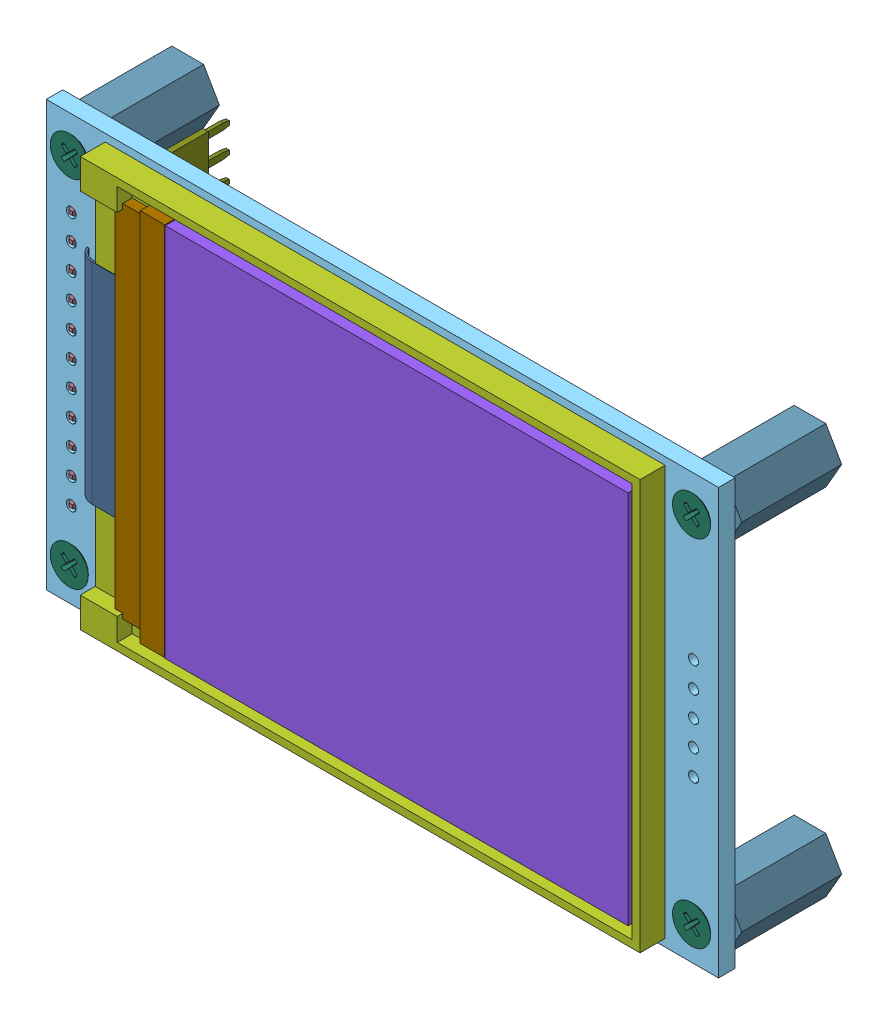
SolidWorks assembly 2.2 TFT LCD Display Modul 240x320, configuration Default. Lengths in mm.
Overall size (68.6 42.5 25.74).
27 component instances, 17 part files, 24 mates.
Components (placement in the parent):
- COMPOUND007-1: COMPOUND007 [Default] at origin size (0.9 1.7 0.55)
- SOLID001-1: SOLID001 [Default] at origin size (0.9 1.7 0.9)
- SD_Card_Slot-1: SD_Card_Slot [Default] at origin (suppressed, hidden)
- PZ_TransistorSMD-1: PZ_TransistorSMD [Default] at origin size (3 2.5 1.11)
- COMPOUND005-1: COMPOUND005 [Default] at origin size (0.9 1.7 0.55)
- Pad010-1: Pad010 [Default] at origin size (67.25 42.5 6.91)
- PZ_TransistorSMD001-1: PZ_TransistorSMD001 [Default] at origin size (2.5 3 1.11)
- Extrude002-1: Extrude002 [Default] at (0.1292 9.9042 1.65) size (56 41 2.5)
- Display001-1: Display001 [Default] at (0.0633 0.4424 2.65) size (46.3 37.5 1.5)
- DisplayConnecter001-1: DisplayConnecter001 [Default] at origin size (5.48 37.5 2.5)
- Body003-1: Body003 [Default] at origin size (5.2 21 3.4)
- COMPOUND004-1: COMPOUND004 [Default] at origin size (0.9 1.7 0.55)
- COMPOUND006-1: COMPOUND006 [Default] at origin size (0.9 1.7 0.55)
- HEADER 11-2: HEADER 11 [Default] at (-31.125 12.7 0.1949) x (0 -1 0) z (1 0 0) size (27.94 12.86 2.54)
- hex spacer standoff nut_M3 L10-1: hex spacer standoff nut_M3 L10 [Default] at (-31.125 -17.75 -10) size (6.35 5.5 10)
- hex spacer standoff nut_M3 L10-2: hex spacer standoff nut_M3 L10 [Default] at (-31.125 17.75 -10) size (6.35 5.5 10)
- hex spacer standoff nut_M3 L10-8: hex spacer standoff nut_M3 L10 [Default] at (31.125 -17.75 -10) size (6.35 5.5 10)
- hex spacer standoff nut_M3 L10-9: hex spacer standoff nut_M3 L10 [Default] at (31.125 17.75 -10) size (6.35 5.5 10)
- M3_3MM-1: M3_3MM [Default] at (-31.125 17.75 1.85) size (3.8 3.8 3.1)
  - Imported_3-1: Imported_3 [Default] at origin size (3.8 3.8 3.1)
- M3_3MM-2: M3_3MM [Default] at (-31.125 -17.75 1.85) size (3.8 3.8 3.1)
  - Imported_3-1: Imported_3 [Default] at origin size (3.8 3.8 3.1)
- M3_3MM-3: M3_3MM [Default] at (31.125 17.75 1.85) size (3.8 3.8 3.1)
  - Imported_3-1: Imported_3 [Default] at origin size (3.8 3.8 3.1)
- M3_3MM-4: M3_3MM [Default] at (31.125 -17.75 1.85) size (3.8 3.8 3.1)
  - Imported_3-1: Imported_3 [Default] at origin size (3.8 3.8 3.1)
- F HEADER 11-4: F HEADER 11 [Default] at (-31.125 0 -10.8051) x (0 1 0) z (1 0 0) size (28.19 16.52 2.5)
Mates (geometry in assembly coordinates):
- Coincident1: coincident aligned: line of Pad010-1 through (-31.125 12.7 1.65) axis (0 0 1); line of HEADER 11-2 through (-31.125 12.7 1.6949) axis (0 0 1)
- Parallel1: parallel aligned: plane of Pad010-1 through (-33.625 -21.25 1.65) normal (-1 0 0); plane of HEADER 11-2 through (-32.395 13.67 -2.3051) normal (-1 0 0)
- Coincident4: coincident anti-aligned: plane of Pad010-1 through (0 0 1.65) normal (0 0 1); plane of Extrude002-1 through (0.1292 9.9042 1.65) normal (0 0 -1)
- Distance1: distance = 0.75 mm: plane of Extrude002-1 through (-27.725 -20.5 4.15) normal (0 -1 0); line of Pad010-1 through (-33.625 -21.25 1.65) axis (1 0 0)
- Coincident6: coincident anti-aligned: plane of Extrude002-1 through (0.1292 9.9042 2.65) normal (0 0 1); plane of Display001-1 through (0.0633 0.4424 2.65) normal (0 0 -1)
- Distance2: distance = 1 mm anti-aligned: plane of Extrude002-1 through (-24.025 19.75 2.65) normal (0 -1 0); plane of Display001-1 through (-19.225 18.75 4.15) normal (0 1 0)
- Distance3: distance = 0.4 mm anti-aligned: plane of Extrude002-1 through (27.475 19.75 2.65) normal (-1 0 0); plane of Display001-1 through (27.075 18.75 4.15) normal (1 0 0)
- Concentric1: concentric aligned: circle of Pad010-1; circle of hex spacer standoff nut_M3 L10-1
- Coincident10: coincident anti-aligned: plane of Pad010-1 through (0 0 0) normal (0 0 -1); plane of hex spacer standoff nut_M3 L10-1 through (-31.125 -17.75 0) normal (0 0 1)
- Concentric2: concentric aligned: circle of Pad010-1; circle of hex spacer standoff nut_M3 L10-2
- Coincident11: coincident anti-aligned: plane of Pad010-1 through (0 0 0) normal (0 0 -1); plane of hex spacer standoff nut_M3 L10-2 through (-31.125 17.75 0) normal (0 0 1)
- Concentric3: concentric aligned: circle of Pad010-1; circle of hex spacer standoff nut_M3 L10-9
- Coincident12: coincident anti-aligned: plane of Pad010-1 through (0 0 0) normal (0 0 -1); plane of hex spacer standoff nut_M3 L10-9 through (31.125 17.75 0) normal (0 0 1)
- Concentric4: concentric aligned: circle of Pad010-1; circle of hex spacer standoff nut_M3 L10-8
- Coincident13: coincident anti-aligned: plane of Pad010-1 through (0 0 0) normal (0 0 -1); plane of hex spacer standoff nut_M3 L10-8 through (31.125 -17.75 0) normal (0 0 1)
- Concentric5: concentric anti-aligned: circle of Pad010-1; circle of M3_3MM-1/Imported_3-1
- Distance4: distance = 0.2 mm aligned: plane of M3_3MM-1/Imported_3-1 through (-31.125 17.75 1.85) normal (0 0 1); plane of Pad010-1 through (0 0 1.65) normal (0 0 1)
- Concentric6: concentric anti-aligned: circle of Pad010-1; circle of M3_3MM-2/Imported_3-1
- Distance5: distance = 0.2 mm aligned: plane of M3_3MM-2/Imported_3-1 through (-31.125 -17.75 1.85) normal (0 0 1); plane of Pad010-1 through (0 0 1.65) normal (0 0 1)
- Concentric8: concentric anti-aligned: circle of Pad010-1; circle of M3_3MM-4/Imported_3-1
- Distance6: distance = 0.2 mm aligned: plane of M3_3MM-4/Imported_3-1 through (31.125 -17.75 1.85) normal (0 0 1); plane of Pad010-1 through (0 0 1.65) normal (0 0 1)
- Concentric9: concentric anti-aligned: circle of Pad010-1; circle of M3_3MM-3/Imported_3-1
- Distance7: distance = 0.2 mm aligned: plane of M3_3MM-3/Imported_3-1 through (31.125 17.75 1.85) normal (0 0 1); plane of Pad010-1 through (0 0 1.65) normal (0 0 1)
- Coincident16: coincident anti-aligned: line of Pad010-1 through (-31.125 12.7 1.65) axis (0 0 1); line of F HEADER 11-4 through (-31.125 12.7 -14.0051) axis (0 0 -1)
